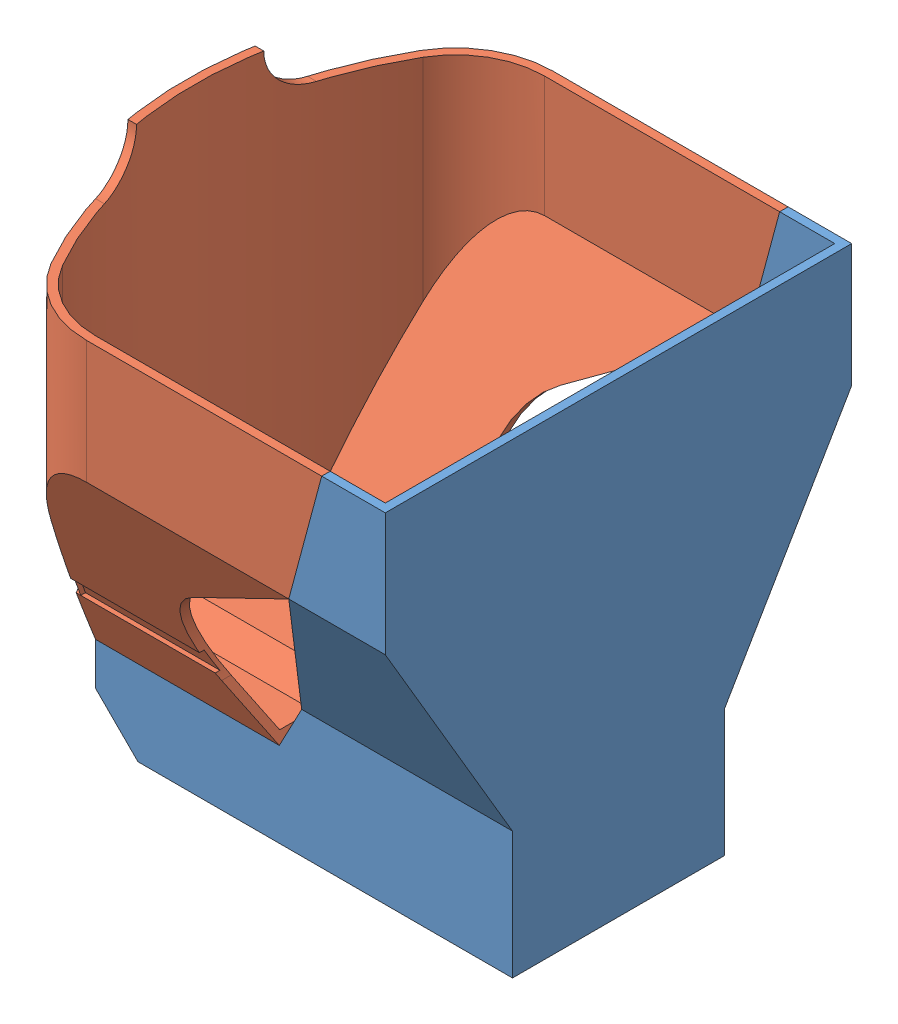
SolidWorks assembly Assem1, configuration Default. Lengths in mm.
Overall size (102 120.62 110).
2 component instances, 2 part files, 3 mates.
Components (placement in the parent):
- Part4-1: Part4 [Default] at (-47.2836 -13.2676 16.3836) size (102 110 110)
- Part3-1: Part3 [Default] at (17.9912 6.7324 24.8755) size (87 100.62 110)
Mates (geometry in assembly coordinates):
- Coincident1: coincident: plane of assembly; plane of assembly; plane of Part4-1 through (17.9912 6.7324 24.8755) normal (0 1 0); plane of Part3-1 through (-37.4344 6.7324 -7.1245) normal (0 -1 0)
- Coincident2: coincident: plane of assembly; point of assembly; plane of Part4-1 through (-22.0088 6.7324 39.8755) normal (1 0 0); point of Part3-1
- Coincident3: coincident: plane of assembly; line of assembly; plane of Part4-1 through (-65.3395 6.7324 49.8755) normal (0 0 1); line of Part3-1 through (-65.3395 6.7324 49.8755) axis (1 0 0)
